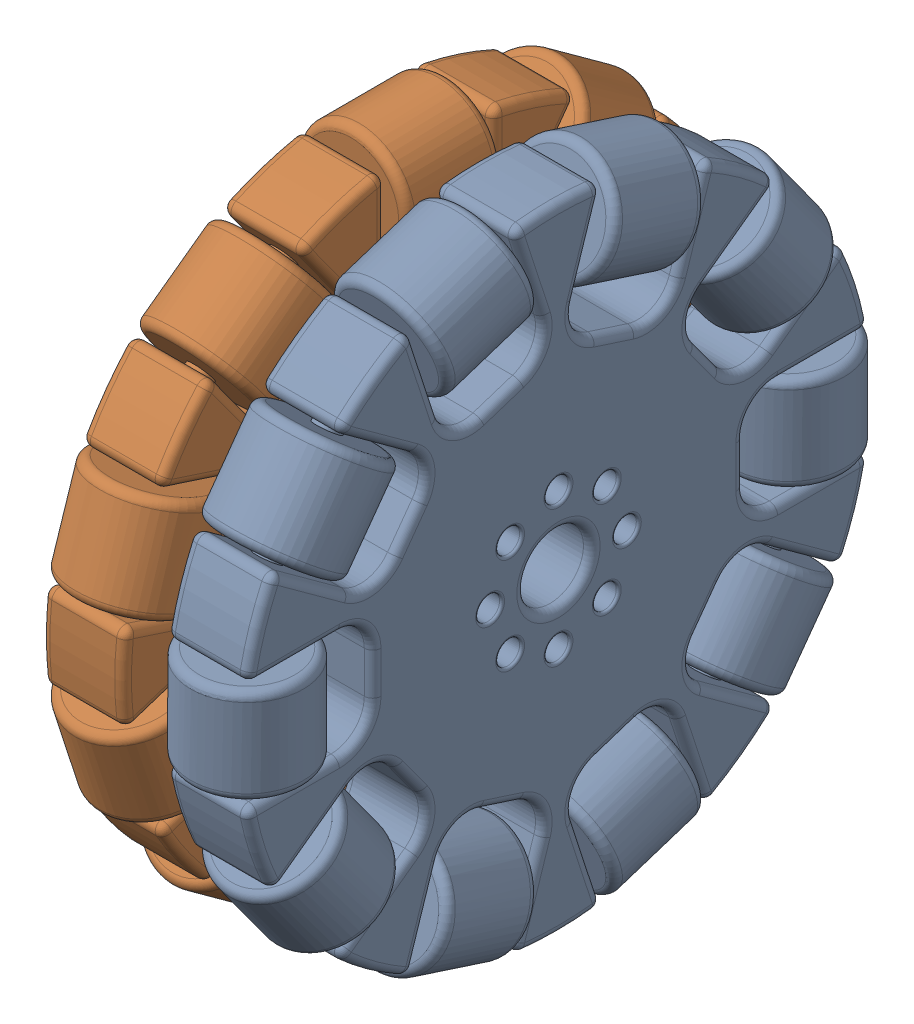
SolidWorks assembly dualOmniWheel_rev5, configuration Default. Lengths in mm.
Overall size (27.8 78.5 78.5).
2 component instances, 1 part files, 5 mates.
Components (placement in the parent):
- singleOmniWheel-1: singleOmniWheel [Default] at (7.15 0 0) x (1 0 0) z (0 1 0) size (13.5 78.5 77.69)
- singleOmniWheel-2: singleOmniWheel [Default] at (-7.15 0 0) size (13.5 78.5 77.69)
Mates (geometry in assembly coordinates):
- Concentric1: concentric aligned: cylinder of singleOmniWheel-1 through (12.05 0 0) axis (-1 0 0) radius 4; cylinder of singleOmniWheel-2 through (-2.25 0 0) axis (-1 0 0) radius 4
- Concentric3: concentric aligned: cylinder of singleOmniWheel-1 through (0.4 8.2125 0) axis (1 0 0) radius 1.4375; cylinder of singleOmniWheel-2 through (-12.05 8.2125 0) axis (1 0 0) radius 1.4375
- Distance3: distance = 2.25 mm: plane of assembly through (0 0 0) normal (1 0 0); plane of assembly; plane of singleOmniWheel-1 through (2.25 0 0) normal (-1 0 0)
- Concentric6: concentric anti-aligned: cylinder of singleOmniWheel-2 through (-2.25 0 0) axis (-1 0 0) radius 4
- Distance7: distance = 2.25 mm: plane of assembly through (0 0 0) normal (1 0 0); plane of assembly; plane of singleOmniWheel-2 through (-2.25 0 0) normal (1 0 0)
